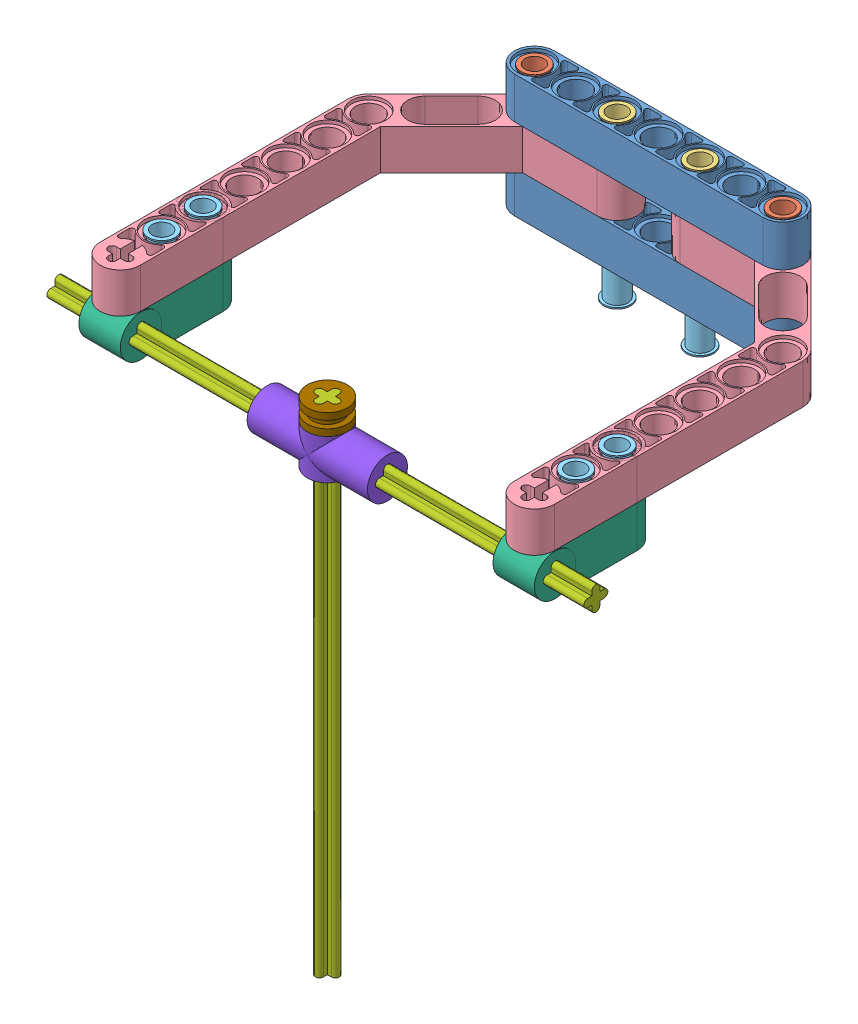
SolidWorks assembly arms_and_chest, configuration Default. Lengths in mm.
Overall size (102.11 106.17 70.74).
23 component instances, 9 part files, 70 mates.
Components (placement in the parent):
- All_Straight-1: All_Straight [Seven] x (1 0 0) z (0 -1 0) size (54.86 7.62 7.87)
- BlueConnectorLong-1: BlueConnectorLong [Default] at (-39.37 -0.254 0) x (0 -1 0) z (0 0 1) size (22.86 5.59 5.59)
- BlueConnectorLong-3: BlueConnectorLong [Default] at (7.874 -0.254 0) x (0 -1 0) z (0 0 1) size (22.86 5.59 5.59)
- BlueConnectorCross_Tube-1: BlueConnectorCross_Tube [Default] at (-23.622 -7.874 0) x (0 1 0) z (0 0 1) size (15.24 5.08 5.08)
- BlueConnectorCross_Tube-2: BlueConnectorCross_Tube [Default] at (-7.874 -7.874 0) x (0 1 0) z (0 0 1) size (15.24 5.08 5.08)
- Three_Four_Seven_90degreesTurn-1: Three_Four_Seven_90degreesTurn [Default] at (-31.496 -15.494 0) x (1 0 0) z (0 1 0) size (39.12 70.61 7.62)
- Three_Four_Seven_90degreesTurn-4: Three_Four_Seven_90degreesTurn [Default] at (0 -7.874 0) x (-1 0 0) z (0 -1 0) size (39.12 70.61 7.62)
- All_Straight-2: All_Straight [Seven] at (0 -23.368 0) x (1 0 0) z (0 1 0) size (54.86 7.62 7.87)
- BlackConnectorSmall-1: BlackConnectorSmall [Default] at (23.622 -7.874 47.244) x (0 -1 0) z (0 0 1) size (15.24 5.59 5.59)
- BlackConnectorSmall-2: BlackConnectorSmall [Default] at (23.622 -7.874 55.118) x (0 -1 0) z (0 0 1) size (15.24 5.59 5.59)
- BlackConnectorSmall-3: BlackConnectorSmall [Default] at (-55.118 -7.874 47.244) x (0 -1 0) z (0 0 1) size (15.24 5.59 5.59)
- BlackConnectorSmall-4: BlackConnectorSmall [Default] at (-55.118 -7.874 55.118) x (0 -1 0) z (0 0 1) size (15.24 5.59 5.59)
- BlackConnectorSmall-5: BlackConnectorSmall [Default] at (-31.496 -23.114 0) x (0 1 0) z (0 0 1) size (15.24 5.59 5.59)
- BlackConnectorSmall-6: BlackConnectorSmall [Default] at (0 -23.114 0) x (0 1 0) z (0 0 1) size (15.24 5.59 5.59)
- StraightTurn_Twohole_1Cross-1: StraightTurn_Twohole_1Cross [Default] at (27.432 -19.431 54.991) x (0 0 1) z (-1 0 0) size (23.5 7.87 7.87)
- StraightTurn_Twohole_1Cross-2: StraightTurn_Twohole_1Cross [Default] at (-51.308 -19.431 54.991) x (0 0 1) z (-1 0 0) size (23.5 7.87 7.87)
- CrossTemplate-1: CrossTemplate [Six] at (-11.938 -19.431 64.516) x (0 0 -1) z (1 0 0) size (4.57 4.57 47.24)
- Cross_AngleHole-1: Cross_AngleHole [Default] at (-4.318 -19.431 61.468) x (0 0 1) z (-1 0 0) size (7.62 7.62 22.86)
- CrossTemplate-2: CrossTemplate [Six] at (-66.802 -19.431 64.516) x (0 0 -1) z (1 0 0) size (4.57 4.57 47.24)
- CrossTemplate-3: CrossTemplate [Twelve] at (-17.272 -11.684 62.992) x (1 0 0) z (0 -1 0) size (4.57 4.57 94.49)
- Light_Gray_X8__Template-1: Light_Gray_X8__Template [half] at (-23.622 -11.684 62.992) x (1 0 0) z (0 -1 0) size (7.62 7.62 3.94)
- BlackConnectorSmall-7: BlackConnectorSmall [Default] at (-7.874 -15.748 0) x (0 -1 0) z (0 0 1) size (15.24 5.59 5.59)
- BlackConnectorSmall-8: BlackConnectorSmall [Default] at (-23.622 -15.748 0) x (0 -1 0) z (0 0 1) size (15.24 5.59 5.59)
Mates (geometry in assembly coordinates):
- Coincident1: coincident aligned: plane of All_Straight-1; plane of assembly through (0 0 0) normal (1 0 0)
- Coincident2: coincident anti-aligned: plane of All_Straight-1 through (0 0 0) normal (0 -1 0); plane of assembly through (0 0 0) normal (0 1 0)
- Coincident3: coincident aligned: plane of All_Straight-1 through (0 0 0) normal (0 0 1); plane of assembly through (0 0 0) normal (0 0 1)
- Parallel1: parallel aligned: plane of BlueConnectorLong-1; plane of assembly through (0 0 0) normal (1 0 0)
- Parallel2: parallel aligned: plane of BlueConnectorLong-3; plane of assembly through (0 0 0) normal (1 0 0)
- Parallel3: parallel anti-aligned: plane of BlueConnectorCross_Tube-1; plane of assembly through (0 0 0) normal (1 0 0)
- Parallel4: parallel anti-aligned: plane of BlueConnectorCross_Tube-2; plane of assembly through (0 0 0) normal (1 0 0)
- Parallel5: parallel aligned: plane of BlackConnectorSmall-1; plane of assembly through (0 0 0) normal (1 0 0)
- Parallel6: parallel aligned: plane of BlackConnectorSmall-2; plane of assembly through (0 0 0) normal (1 0 0)
- Parallel7: parallel aligned: plane of BlackConnectorSmall-3; plane of assembly through (0 0 0) normal (1 0 0)
- Parallel8: parallel aligned: plane of BlackConnectorSmall-4; plane of assembly through (0 0 0) normal (1 0 0)
- Parallel9: parallel anti-aligned: plane of BlackConnectorSmall-5; plane of assembly through (0 0 0) normal (1 0 0)
- Parallel10: parallel anti-aligned: plane of BlackConnectorSmall-6; plane of assembly through (0 0 0) normal (1 0 0)
- Tangent1: tangent anti-aligned: plane of CrossTemplate-1 through (-11.938 -19.431 64.516) normal (-1 0 0); cylinder of Cross_AngleHole-1 through (-15.748 -23.241 62.992) axis (0 1 0) radius 3.81
- Tangent2: tangent anti-aligned: cylinder of Cross_AngleHole-1 through (-15.748 -23.241 62.992) axis (0 1 0) radius 3.81; plane of CrossTemplate-2 through (-19.558 -19.431 64.516) normal (1 0 0)
- Width1: width anti-aligned: plane of StraightTurn_Twohole_1Cross-2 through (-51.308 -28.304 62.9285) normal (1 0 0); plane of StraightTurn_Twohole_1Cross-1 through (19.812 -28.304 62.9285) normal (-1 0 0); plane of Cross_AngleHole-1 through (-27.178 -27.9544 62.992) normal (-1 0 0); plane of Cross_AngleHole-1 through (-4.318 -27.9544 62.992) normal (1 0 0)
- Parallel11: parallel aligned: plane of Light_Gray_X8__Template-1 through (-23.622 -11.684 62.992) normal (0 0 1); plane of assembly through (0 0 0) normal (0 0 1)
- Concentric1: concentric aligned: cylinder of All_Straight-1 through (-39.37 -3.937 0) axis (0 1 0) radius 2.54; cylinder of BlueConnectorLong-1 through (-39.37 -0.254 0) axis (0 1 0) radius 2.032
- Coincident4: coincident anti-aligned: plane of All_Straight-1 through (-39.37 -7.239 0) normal (0 -1 0); plane of BlueConnectorLong-1 through (-36.576 -7.239 0) normal (0 1 0)
- Concentric2: concentric anti-aligned: cylinder of All_Straight-1 through (-23.622 -3.937 0) axis (0 1 0) radius 2.54; cylinder of BlueConnectorCross_Tube-1 through (-23.622 -7.874 0) axis (0 -1 0) radius 2.032
- Coincident5: coincident anti-aligned: plane of All_Straight-1 through (-23.622 -7.239 0) normal (0 -1 0); plane of BlueConnectorCross_Tube-1 through (-26.162 -7.239 0) normal (0 1 0)
- Concentric3: concentric anti-aligned: cylinder of All_Straight-1 through (-7.874 -3.937 0) axis (0 1 0) radius 2.54; cylinder of BlueConnectorCross_Tube-2 through (-7.874 -7.874 0) axis (0 -1 0) radius 2.032
- Coincident6: coincident anti-aligned: plane of All_Straight-1 through (-7.874 -7.239 0) normal (0 -1 0); plane of BlueConnectorCross_Tube-2 through (-10.414 -7.239 0) normal (0 1 0)
- Concentric4: concentric aligned: cylinder of All_Straight-1 through (7.874 -3.937 0) axis (0 1 0) radius 2.54; cylinder of BlueConnectorLong-3 through (7.874 -0.254 0) axis (0 1 0) radius 2.032
- Coincident7: coincident anti-aligned: plane of All_Straight-1 through (7.874 -7.239 0) normal (0 -1 0); plane of BlueConnectorLong-3 through (10.668 -7.239 0) normal (0 1 0)
- Concentric5: concentric aligned: cylinder of BlueConnectorCross_Tube-2 through (-7.874 -15.494 -1.524) axis (0 1 0) radius 0.762; cylinder of Three_Four_Seven_90degreesTurn-4 through (-7.874 -11.684 -1.524) axis (0 1 0) radius 0.762
- Coincident9: coincident anti-aligned: plane of BlueConnectorCross_Tube-2 through (-7.112 -15.494 -0.762) normal (1 0 0); plane of Three_Four_Seven_90degreesTurn-4 through (-7.112 -11.684 22.6846) normal (-1 0 0)
- Concentric6: concentric aligned: cylinder of BlueConnectorLong-3 through (7.874 -0.254 0) axis (0 1 0) radius 2.032; cylinder of Three_Four_Seven_90degreesTurn-4 through (7.874 -11.684 0) axis (0 1 0) radius 2.54
- Coincident10: coincident anti-aligned: plane of BlueConnectorLong-3 through (9.906 -8.509 0) normal (0 -1 0); plane of Three_Four_Seven_90degreesTurn-4 through (7.874 -8.509 0) normal (0 1 0)
- Concentric7: concentric anti-aligned: cylinder of BlueConnectorCross_Tube-1 through (-23.622 -15.494 1.524) axis (0 1 0) radius 0.762; cylinder of Three_Four_Seven_90degreesTurn-1 through (-23.622 -11.684 1.524) axis (0 -1 0) radius 0.762
- Coincident11: coincident anti-aligned: plane of BlueConnectorCross_Tube-1 through (-22.86 -15.494 1.524) normal (1 0 0); plane of Three_Four_Seven_90degreesTurn-1 through (-22.86 -11.684 22.6846) normal (-1 0 0)
- Concentric8: concentric anti-aligned: cylinder of BlueConnectorLong-1 through (-39.37 -0.254 0) axis (0 1 0) radius 2.032; cylinder of Three_Four_Seven_90degreesTurn-1 through (-39.37 -11.684 0) axis (0 -1 0) radius 2.54
- Coincident12: coincident anti-aligned: plane of BlueConnectorLong-1 through (-37.338 -8.509 0) normal (0 -1 0); plane of Three_Four_Seven_90degreesTurn-1 through (-39.37 -8.509 0) normal (0 1 0)
- Concentric9: concentric aligned: cylinder of BlackConnectorSmall-5 through (-31.496 -23.114 0) axis (0 -1 0) radius 2.032; cylinder of All_Straight-2 through (-31.496 -19.431 0) axis (0 -1 0) radius 2.54
- Concentric10: concentric aligned: cylinder of BlackConnectorSmall-6 through (0 -23.114 0) axis (0 -1 0) radius 2.032; cylinder of All_Straight-2 through (0 -19.431 0) axis (0 -1 0) radius 2.54
- Coincident13: coincident anti-aligned: plane of All_Straight-2 through (-31.496 -16.129 0) normal (0 1 0); plane of BlackConnectorSmall-5 through (-34.29 -16.129 0) normal (0 -1 0)
- Coincident14: coincident anti-aligned: plane of All_Straight-2 through (0 -16.129 0) normal (0 1 0); plane of BlackConnectorSmall-6 through (-2.794 -16.129 0) normal (0 -1 0)
- Concentric11: concentric aligned: cylinder of Three_Four_Seven_90degreesTurn-1 through (-31.496 -11.684 0) axis (0 -1 0) radius 2.54; cylinder of BlackConnectorSmall-5 through (-31.496 -23.114 0) axis (0 -1 0) radius 2.032
- Concentric12: concentric anti-aligned: cylinder of Three_Four_Seven_90degreesTurn-4 through (0 -11.684 0) axis (0 1 0) radius 2.54; cylinder of BlackConnectorSmall-6 through (0 -23.114 0) axis (0 -1 0) radius 2.032
- Coincident15: coincident anti-aligned: plane of Three_Four_Seven_90degreesTurn-1 through (-31.496 -14.859 0) normal (0 -1 0); plane of BlackConnectorSmall-5 through (-33.528 -14.859 0) normal (0 1 0)
- Concentric13: concentric anti-aligned: cylinder of Three_Four_Seven_90degreesTurn-1 through (-55.118 -11.684 47.244) axis (0 -1 0) radius 2.54; cylinder of BlackConnectorSmall-3 through (-55.118 -7.874 47.244) axis (0 1 0) radius 2.032
- Coincident16: coincident anti-aligned: plane of Three_Four_Seven_90degreesTurn-1 through (-55.118 -14.859 47.244) normal (0 -1 0); plane of BlackConnectorSmall-3 through (-52.324 -14.859 47.244) normal (0 1 0)
- Concentric14: concentric anti-aligned: cylinder of Three_Four_Seven_90degreesTurn-1 through (-55.118 -11.684 55.118) axis (0 -1 0) radius 2.54; cylinder of BlackConnectorSmall-4 through (-55.118 -7.874 55.118) axis (0 1 0) radius 2.032
- Coincident17: coincident anti-aligned: plane of Three_Four_Seven_90degreesTurn-1 through (-55.118 -14.859 55.118) normal (0 -1 0); plane of BlackConnectorSmall-4 through (-52.324 -14.859 55.118) normal (0 1 0)
- Concentric15: concentric aligned: cylinder of Three_Four_Seven_90degreesTurn-4 through (23.622 -11.684 47.244) axis (0 1 0) radius 2.54; cylinder of BlackConnectorSmall-1 through (23.622 -7.874 47.244) axis (0 1 0) radius 2.032
- Coincident18: coincident anti-aligned: plane of Three_Four_Seven_90degreesTurn-4 through (23.622 -14.859 47.244) normal (0 -1 0); plane of BlackConnectorSmall-1 through (26.416 -14.859 47.244) normal (0 1 0)
- Concentric16: concentric aligned: cylinder of Three_Four_Seven_90degreesTurn-4 through (23.622 -11.684 55.118) axis (0 1 0) radius 2.54; cylinder of BlackConnectorSmall-2 through (23.622 -7.874 55.118) axis (0 1 0) radius 2.032
- Coincident19: coincident anti-aligned: plane of Three_Four_Seven_90degreesTurn-4 through (23.622 -14.859 55.118) normal (0 -1 0); plane of BlackConnectorSmall-2 through (26.416 -14.859 55.118) normal (0 1 0)
- Concentric17: concentric anti-aligned: cylinder of BlackConnectorSmall-3 through (-55.118 -7.874 47.244) axis (0 1 0) radius 2.032; cylinder of StraightTurn_Twohole_1Cross-2 through (-55.118 -19.431 47.244) axis (0 -1 0) radius 2.54
- Concentric18: concentric anti-aligned: cylinder of BlackConnectorSmall-4 through (-55.118 -7.874 55.118) axis (0 1 0) radius 2.032; cylinder of StraightTurn_Twohole_1Cross-2 through (-55.118 -19.431 55.118) axis (0 -1 0) radius 2.54
- Concentric19: concentric anti-aligned: cylinder of BlackConnectorSmall-1 through (23.622 -7.874 47.244) axis (0 1 0) radius 2.032; cylinder of StraightTurn_Twohole_1Cross-1 through (23.622 -19.431 47.244) axis (0 -1 0) radius 2.54
- Concentric20: concentric anti-aligned: cylinder of BlackConnectorSmall-2 through (23.622 -7.874 55.118) axis (0 1 0) radius 2.032; cylinder of StraightTurn_Twohole_1Cross-1 through (23.622 -19.431 55.118) axis (0 -1 0) radius 2.54
- Coincident20: coincident anti-aligned: plane of BlackConnectorSmall-3 through (-53.086 -16.129 47.244) normal (0 -1 0); plane of StraightTurn_Twohole_1Cross-2 through (-55.118 -16.129 47.244) normal (0 1 0)
- Coincident21: coincident anti-aligned: plane of BlackConnectorSmall-1 through (25.654 -16.129 47.244) normal (0 -1 0); plane of StraightTurn_Twohole_1Cross-1 through (23.622 -16.129 47.244) normal (0 1 0)
- Concentric21: concentric anti-aligned: cylinder of StraightTurn_Twohole_1Cross-1 through (23.622 -17.907 62.992) axis (1 0 0) radius 0.762; cylinder of CrossTemplate-1 through (35.306 -17.907 62.992) axis (-1 0 0) radius 0.762
- Coincident22: coincident anti-aligned: plane of StraightTurn_Twohole_1Cross-1 through (23.622 -28.304 63.754) normal (0 0 -1); plane of CrossTemplate-1 through (35.306 -19.431 63.754) normal (0 0 1)
- Concentric22: concentric aligned: cylinder of CrossTemplate-3 through (-15.748 -106.172 61.468) axis (0 1 0) radius 0.762; cylinder of Light_Gray_X8__Template-1 through (-15.748 -13.6525 61.468) axis (0 1 0) radius 0.762
- Coincident23: coincident anti-aligned: plane of CrossTemplate-3 through (-14.986 -106.172 62.992) normal (1 0 0); plane of Light_Gray_X8__Template-1 through (-14.986 -13.6525 62.992) normal (-1 0 0)
- Coincident24: coincident aligned: plane of CrossTemplate-3 through (-17.272 -11.684 62.992) normal (0 1 0); plane of Light_Gray_X8__Template-1 through (-23.622 -11.684 62.992) normal (0 1 0)
- Concentric23: concentric anti-aligned: cylinder of Cross_AngleHole-1 through (-15.748 -23.241 62.992) axis (0 1 0) radius 2.54; cylinder of Light_Gray_X8__Template-1 through (-15.748 -14.351 62.992) axis (0 -1 0) radius 3.81
- Coincident25: coincident anti-aligned: plane of Cross_AngleHole-1 through (-15.748 -15.621 62.992) normal (0 1 0); plane of Light_Gray_X8__Template-1 through (-23.622 -15.621 62.992) normal (0 -1 0)
- Concentric24: concentric anti-aligned: cylinder of CrossTemplate-1 through (35.306 -19.431 61.468) axis (-1 0 0) radius 0.762; cylinder of Cross_AngleHole-1 through (-27.178 -19.431 61.468) axis (1 0 0) radius 0.762
- Concentric25: concentric anti-aligned: cylinder of StraightTurn_Twohole_1Cross-2 through (-55.118 -17.907 62.992) axis (1 0 0) radius 0.762; cylinder of CrossTemplate-2 through (-19.558 -17.907 62.992) axis (-1 0 0) radius 0.762
- Coincident26: coincident anti-aligned: plane of StraightTurn_Twohole_1Cross-2 through (-55.118 -28.304 63.754) normal (0 0 -1); plane of CrossTemplate-2 through (-19.558 -19.431 63.754) normal (0 0 1)
- Concentric26: concentric anti-aligned: cylinder of All_Straight-2 through (-23.622 -19.431 0) axis (0 -1 0) radius 2.54; cylinder of BlackConnectorSmall-8 through (-23.622 -15.748 0) axis (0 1 0) radius 2.032
- Coincident27: coincident anti-aligned: plane of All_Straight-2 through (-23.622 -22.733 0) normal (0 -1 0); plane of BlackConnectorSmall-8 through (-20.828 -22.733 0) normal (0 1 0)
- Parallel12: parallel aligned: plane of BlackConnectorSmall-8 through (-23.622 -15.748 0) normal (0 0 1); plane of assembly through (0 0 0) normal (0 0 1)
- Concentric27: concentric anti-aligned: cylinder of All_Straight-2 through (-7.874 -19.431 0) axis (0 -1 0) radius 2.54; cylinder of BlackConnectorSmall-7 through (-7.874 -15.748 0) axis (0 1 0) radius 2.032
- Coincident28: coincident anti-aligned: plane of All_Straight-2 through (-7.874 -22.733 0) normal (0 -1 0); plane of BlackConnectorSmall-7 through (-5.08 -22.733 0) normal (0 1 0)
- Parallel13: parallel aligned: plane of BlackConnectorSmall-7 through (-7.874 -15.748 0) normal (0 0 1); plane of assembly through (0 0 0) normal (0 0 1)
